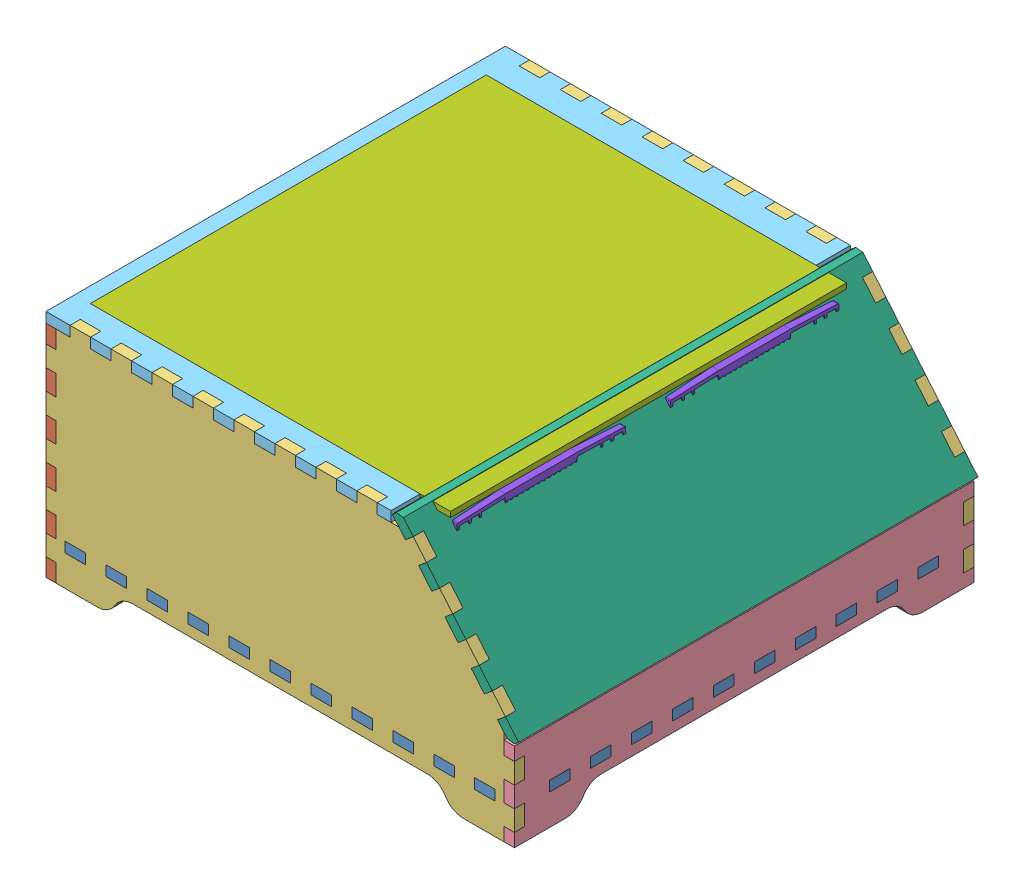
SolidWorks assembly Full box, configuration Default. Lengths in mm.
Overall size (263.77 130.91 256.43).
31 component instances, 11 part files, 20 mates.
Components (placement in the parent):
- Bottom panel-1: Bottom panel [Default] at (-420.1497 291.9295 324.4783) x (1 0 0) z (0 -1 0) size (261.43 256.43 5.71)
- Backplate-1: Backplate [Default] at (124.5381 1548.3595 324.4783) x (0 -1 0) z (-1 0 0) size (122.86 256.43 5.71)
- Side panel-1: Side panel [Default] at (108.4233 245.8701 598.3944) size (261.43 128.58 5.71)
- Side panel-2: Side panel [Default] at (108.4233 245.8701 347.6786) size (261.43 128.58 5.71)
- Front-1: Front [Default] at (380.2526 -534.189 627.3098) x (0 1 0) z (-1 0 0) size (49.19 256.43 5.71)
- Top-1: Top [Default] at (1272.3946 397.643 627.3101) x (-1 0 0) z (0 -1 0) size (192.6 256.43 5.71)
- Panel-1: Panel [Default] at (-237.6481 1051.5124 627.3098) x (0.642783 -0.766048 0) z (0.766048 0.642783 0) size (102.81 256.43 5.71)
- Peltier assembly-1: Peltier assembly [Default] at (403.4403 497.3389 568.8145) x (0 0 -1) z (-1 0 0) size (238 60.94 201)
  - Cold plate-1: Cold plate [Default] at (91.398 99.6959 175.559) size (221 3 201)
  - Heatsink-1: Heatsink [Default] at (31.898 106.6959 75.309) size (119 27.24 200.5)
  - Heatsink-2: Heatsink [Default] at (150.898 106.6959 75.309) size (119 27.24 200.5)
  - 92mm Fan Guard-1: 92mm Fan Guard [Default] at (32.0916 156.652 125.8154) x (0.999999 0 0.001368) z (-0.001368 0 0.999999) size (90.49 4.78 90.49)
  - F9-1: F9 [Default] at (64.0963 125.1552 120.7546) size (93.27 26.59 93.52)
    - F9.STEP-1: F9.STEP [Default] at origin size (93.27 26.59 93.52)
      - F9 body.STEP-1: F9 body.STEP [Default] at (-78.1983 5.7094 50.7544) size (92.01 26.59 92.01)
      - F9 fan.STEP-1: F9 fan.STEP [Default] at (-74.2115 10.4094 -44.9134) x (-0.083202 0 0.996533) z (-0.996533 0 -0.083202) size (86.63 20 86.36)
  - F9-2: F9 [Default] at (64.0963 125.1552 220.8546) size (93.27 26.59 93.52)
    - F9.STEP-1: F9.STEP [Default] at origin size (93.27 26.59 93.52)
      - F9 body.STEP-1: F9 body.STEP [Default] at (-78.1983 5.7094 50.7544) size (92.01 26.59 92.01)
      - F9 fan.STEP-1: F9 fan.STEP [Default] at (-74.2115 10.4094 -44.9134) x (-0.083202 0 0.996533) z (-0.996533 0 -0.083202) size (86.63 20 86.36)
  - F9-3: F9 [Default] at (183.0963 125.1552 120.7546) size (93.27 26.59 93.52)
    - F9.STEP-1: F9.STEP [Default] at origin size (93.27 26.59 93.52)
      - F9 body.STEP-1: F9 body.STEP [Default] at (-78.1983 5.7094 50.7544) size (92.01 26.59 92.01)
      - F9 fan.STEP-1: F9 fan.STEP [Default] at (-74.2115 10.4094 -44.9134) x (-0.083202 0 0.996533) z (-0.996533 0 -0.083202) size (86.63 20 86.36)
  - F9-4: F9 [Default] at (183.0963 125.1552 220.8546) size (93.27 26.59 93.52)
    - F9.STEP-1: F9.STEP [Default] at origin size (93.27 26.59 93.52)
      - F9 body.STEP-1: F9 body.STEP [Default] at (-78.1983 5.7094 50.7544) size (92.01 26.59 92.01)
      - F9 fan.STEP-1: F9 fan.STEP [Default] at (-74.2115 10.4094 -44.9134) x (-0.083202 0 0.996533) z (-0.996533 0 -0.083202) size (86.63 20 86.36)
  - 92mm Fan Guard-3: 92mm Fan Guard [Default] at (151.148 156.652 225.859) size (90.49 4.78 90.49)
  - 92mm Fan Guard-4: 92mm Fan Guard [Default] at (150.6091 156.652 125.7201) x (1 0 0.000944) z (-0.000944 0 1) size (90.49 4.78 90.49)
  - 92mm Fan Guard-5: 92mm Fan Guard [Default] at (32.2135 156.652 225.7935) x (0.999999 0 -0.001588) z (0.001588 0 0.999999) size (90.49 4.78 90.49)
Mates (geometry in assembly coordinates):
- Coincident2: coincident anti-aligned: plane of Bottom panel-1 through (124.5381 286.2145 324.4783) normal (-1 0 0); plane of Backplate-1 through (124.5381 1548.3595 324.4783) normal (1 0 0)
- Coincident3: coincident aligned: plane of Bottom panel-1 through (-420.1497 286.2145 598.3944) normal (0 0 1); plane of Backplate-1 through (118.8231 279.0656 598.3944) normal (0 0 1)
- Width1: width aligned: plane of Bottom panel-1 through (-420.1497 291.9295 324.4783) normal (0 1 0); plane of Backplate-1 through (-420.1497 286.2145 324.4783) normal (0 -1 0); plane of Bottom panel-1 through (118.8231 286.2157 578.7628) normal (0 1 0); plane of Backplate-1 through (118.8231 291.9282 573.0488) normal (0 -1 0)
- Coincident4: coincident anti-aligned: plane of Bottom panel-1 through (-420.1497 286.2145 598.3944) normal (0 0 1); plane of Side panel-1 through (108.4233 245.8701 598.3944) normal (0 0 -1)
- Coincident5: coincident anti-aligned: plane of Backplate-1 through (124.5381 1548.3595 324.4783) normal (1 0 0); plane of Side panel-1 through (124.5381 324.7861 604.1094) normal (-1 0 0)
- Coincident6: coincident aligned: plane of Backplate-1 through (118.8231 269.0707 575.5334) normal (0 -1 0); plane of Side panel-1 through (147.3981 269.0707 604.1094) normal (0 -1 0)
- Coincident7: coincident anti-aligned: plane of Bottom panel-1 through (-420.1497 286.2145 353.3936) normal (0 0 -1); plane of Side panel-2 through (108.4233 245.8701 353.3936) normal (0 0 1)
- Coincident8: coincident anti-aligned: plane of Backplate-1 through (124.5381 1548.3595 324.4783) normal (1 0 0); plane of Side panel-2 through (124.5381 301.9259 353.3936) normal (-1 0 0)
- Coincident9: coincident aligned: plane of Backplate-1 through (118.8231 269.0707 376.2541) normal (0 -1 0); plane of Side panel-2 through (147.3981 269.0707 353.3936) normal (0 -1 0)
- Coincident10: coincident anti-aligned: plane of Bottom panel-1 through (374.5376 286.2145 324.4783) normal (1 0 0); plane of Front-1 through (374.5376 -534.189 627.3098) normal (-1 0 0)
- Coincident11: coincident anti-aligned: plane of Side panel-1 through (108.4233 245.8701 598.3944) normal (0 0 -1); plane of Front-1 through (374.5376 299.3831 598.3944) normal (0 0 1)
- Coincident12: coincident aligned: plane of Side panel-1 through (351.6788 269.0707 604.1094) normal (0 -1 0); plane of Front-1 through (374.5376 269.0707 574.7943) normal (0 -1 0)
- Coincident13: coincident anti-aligned: plane of Backplate-1 through (118.8231 391.928 604.1094) normal (0 1 0); plane of Top-1 through (1272.3946 391.928 627.3101) normal (0 -1 0)
- Coincident14: coincident aligned: plane of Backplate-1 through (118.8231 1548.3595 324.4783) normal (-1 0 0); plane of Top-1 through (118.8231 391.928 627.3101) normal (-1 0 0)
- Coincident15: coincident aligned: plane of Side panel-1 through (108.4233 245.8701 604.1094) normal (0 0 1); plane of Top-1 through (1272.3946 391.928 604.1094) normal (0 0 1)
- Coincident26: coincident anti-aligned: plane of Side panel-1 through (108.4233 245.8701 598.3944) normal (0 0 -1); plane of Panel-1 through (323.8326 391.249 598.3944) normal (0 0 1)
- Coincident29: coincident aligned: line of Side panel-1 through (323.8326 391.249 604.1094) axis (0 0 -1); line of Panel-1 through (323.8326 391.249 604.1091) axis (0 0 -1)
- Coincident30: coincident: line of Side panel-1 through (374.5366 321.9306 604.1094) axis (0 0 -1); plane of Panel-1 through (-237.6481 1051.5124 627.3098) normal (-0.766048 -0.642783 0)
- Coincident31: coincident aligned: plane of Top-1 through (1272.3946 397.643 627.3101) normal (0 1 0); plane of Peltier assembly-1/Cold plate-1 through (227.8813 397.643 477.4165) normal (0 1 0)
- Parallel8: parallel aligned: plane of Backplate-1 through (118.8231 1548.3595 324.4783) normal (-1 0 0); plane of Peltier assembly-1/Cold plate-1 through (127.3813 394.643 587.9165) normal (-1 0 0)
